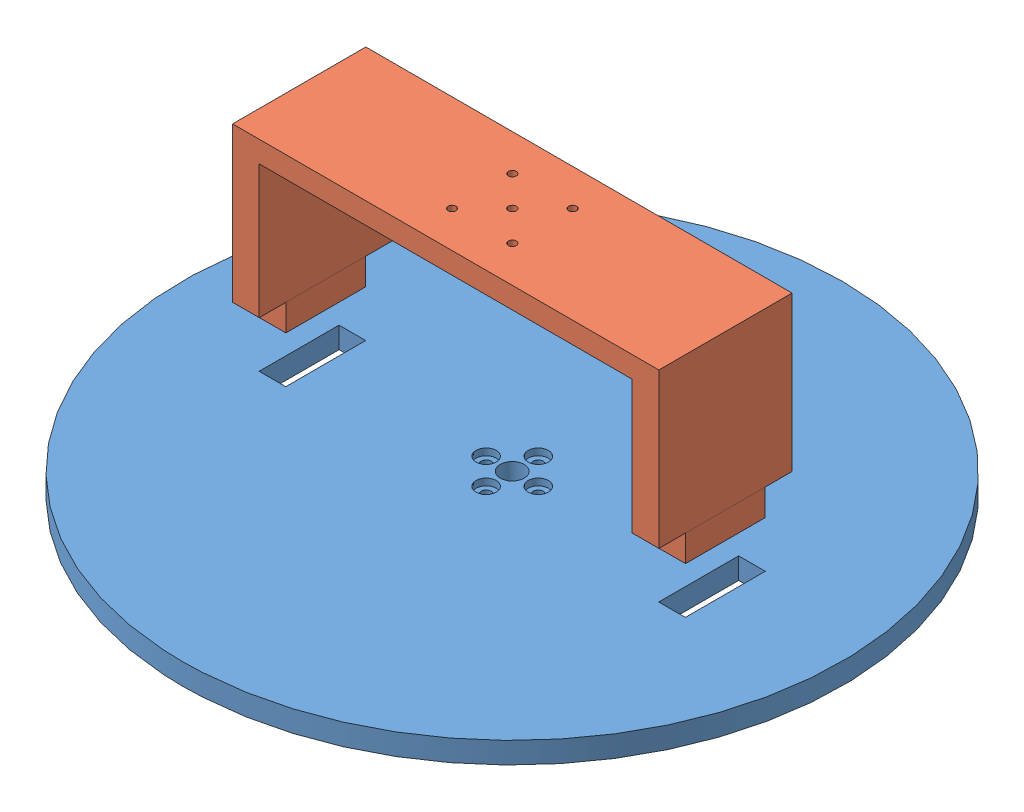
SolidWorks assembly scaled_platform_assembly, configuration Default. Lengths in mm.
Overall size (247.5 93.4 247.5).
2 component instances, 2 part files, 6 mates.
Components (placement in the parent):
- Scaled_Platform_baseOnly-1: Scaled_Platform_baseOnly [Default] at origin size (247.5 8 247.5)
- scaled_platform_bridgeOnly-1: scaled_platform_bridgeOnly [Default] at (0 93.4 -0.05) x (1 0 0) z (0 0 -1) size (160 68 50)
Mates (geometry in assembly coordinates):
- Parallel1: parallel aligned: plane of scaled_platform_bridgeOnly-1 through (80 85.4 24.95) normal (0 0 1)
- Parallel2: parallel aligned: plane of scaled_platform_bridgeOnly-1 through (0 93.4 -0.05) normal (0 1 0)
- Parallel3: parallel aligned: plane of scaled_platform_bridgeOnly-1 through (80 85.4 -25.05) normal (1 0 0)
- Coincident4: coincident anti-aligned: plane of Scaled_Platform_baseOnly-1 through (-80 0 15) normal (1 0 0); plane of scaled_platform_bridgeOnly-1 through (-80 85.4 -25.05) normal (-1 0 0)
- Coincident5: coincident anti-aligned: plane of Scaled_Platform_baseOnly-1 through (-80 0 -15) normal (0 0 1); plane of scaled_platform_bridgeOnly-1 through (-70.05 25.4 -15) normal (0 0 -1)
- LimitDistance1: limit distance = 25.4 mm aligned: plane of scaled_platform_bridgeOnly-1 through (0 25.4 -0.05) normal (0 -1 0); plane of Scaled_Platform_baseOnly-1 through (0 0 0) normal (0 -1 0)
